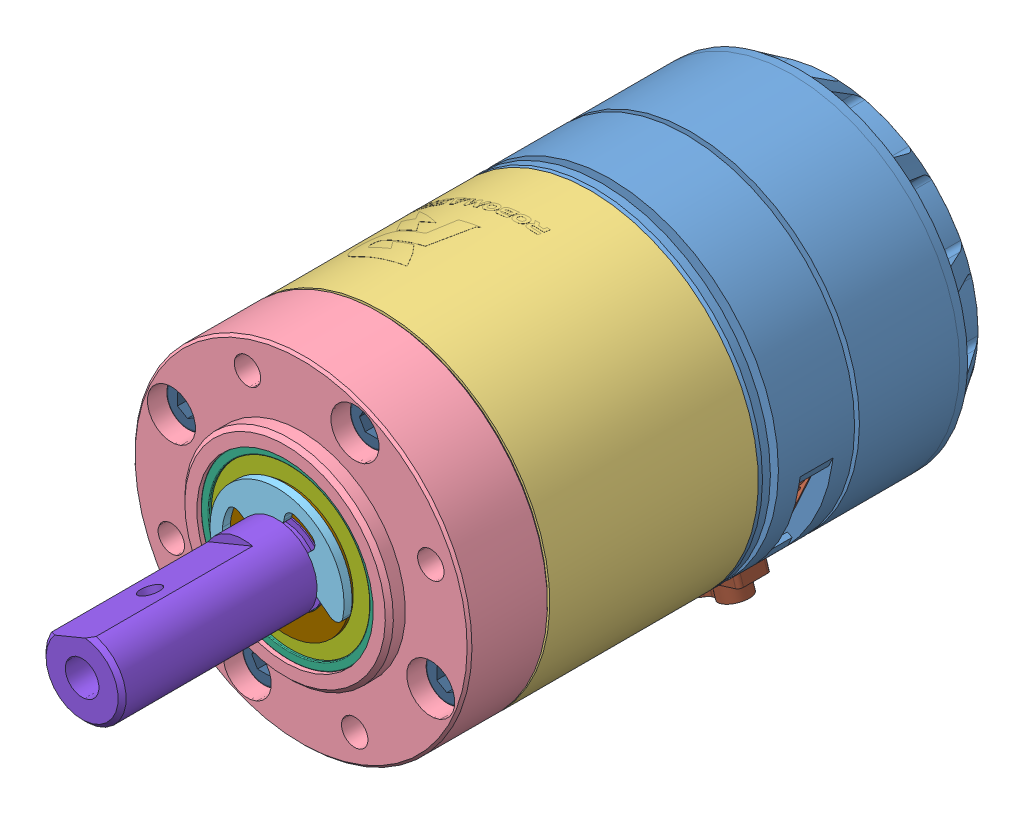
SolidWorks assembly RoboMaster M3508 P19 Brushless DC Gear Motor, configuration ﾃﾞﾌｫﾙﾄ. Lengths in mm.
Overall size (77.57 77.57 98.4).
22 component instances, 11 part files, 0 mates.
Components (placement in the parent):
- 1-1: 1 [ﾃﾞﾌｫﾙﾄ] at (-1.7887 18.2683 48.441) x (0.923508 -0.383579 0) z (0 0 1) size (42 42 43.41)
- 4-1: 4 [ﾃﾞﾌｫﾙﾄ] at (-1.7887 18.2683 39.841) x (-0.923508 0.383579 0) z (0.383579 0.923508 0) size (13.16 4.25 21.29)
- 2-1: 2 [ﾃﾞﾌｫﾙﾄ] at (-1.7887 18.2683 50.441) x (-0.381788 0.92425 0) z (0.92425 0.381788 0) size (59.4 63.3 59.4)
  - 23-1: 23 [ﾃﾞﾌｫﾙﾄ] at origin size (42.01 26 42)
  - 16-1: 16 [ﾃﾞﾌｫﾙﾄ] at (0 31 0) x (-0.707107 0 0.707107) z (0 1 0) size (42 42 14)
  - 25-1: 25 [ﾃﾞﾌｫﾙﾄ] at (0 38.5 0) x (0 0 1) z (-1 0 0) size (16.7 1 13.43)
  - 26-1: 26 [ﾃﾞﾌｫﾙﾄ] at (0 27 0) x (-0.381788 0 0.92425) z (-0.92425 0 -0.381788) size (22 6 22)
    - 27-1: 27 [ﾃﾞﾌｫﾙﾄ] at origin size (22 6 22)
    - 28-1: 28 [ﾃﾞﾌｫﾙﾄ] at (0 2.5 0) size (20 0.2 20)
    - 28-2: 28 [ﾃﾞﾌｫﾙﾄ] at (0 -2.7 0) size (20 0.2 20)
  - 26-2: 26 [ﾃﾞﾌｫﾙﾄ] at (0 34.5 0) x (-0.381788 0 0.92425) z (-0.92425 0 -0.381788) size (22 6 22)
    - 27-1: 27 [ﾃﾞﾌｫﾙﾄ] at origin size (22 6 22)
    - 28-1: 28 [ﾃﾞﾌｫﾙﾄ] at (0 2.5 0) size (20 0.2 20)
    - 28-2: 28 [ﾃﾞﾌｫﾙﾄ] at (0 -2.7 0) size (20 0.2 20)
  - 17-1: 17 [ﾃﾞﾌｫﾙﾄ] at (0 19.3 0) x (-1 0 0) z (0 0 -1) size (26 44 26)
  - 24-1: 24 [ﾃﾞﾌｫﾙﾄ] at (0 37.71 0) x (0 1 0) z (0.381788 0 -0.92425) size (0.42 16 16)
  - 18-1: 18 [ﾃﾞﾌｫﾙﾄ] at (12.3744 22 12.3744) x (-0.381788 0 0.92425) z (-0.92425 0 -0.381788) size (5.5 12 5.5)
  - 18-2: 18 [ﾃﾞﾌｫﾙﾄ] at (12.3744 22 -12.3744) x (0.92425 0 0.381788) z (-0.381788 0 0.92425) size (5.5 12 5.5)
  - 18-3: 18 [ﾃﾞﾌｫﾙﾄ] at (-12.3744 22 -12.3744) x (0.381788 0 -0.92425) z (0.92425 0 0.381788) size (5.5 12 5.5)
  - 18-4: 18 [ﾃﾞﾌｫﾙﾄ] at (-12.3744 22 12.3744) x (-0.92425 0 -0.381788) z (0.381788 0 -0.92425) size (5.5 12 5.5)
- 3-1: 3 [ﾃﾞﾌｫﾙﾄ] at (4.5067 -1.7659 43.091) x (0.299781 -0.954008 0) z (0.954008 0.299781 0) size (5.77 4 14.5)
- 5-1: 5 [ﾃﾞﾌｫﾙﾄ] at (56.824 -105.7062 43.091) x (0.954008 0.299781 0) z (-0.299781 0.954008 0) (suppressed, hidden)
